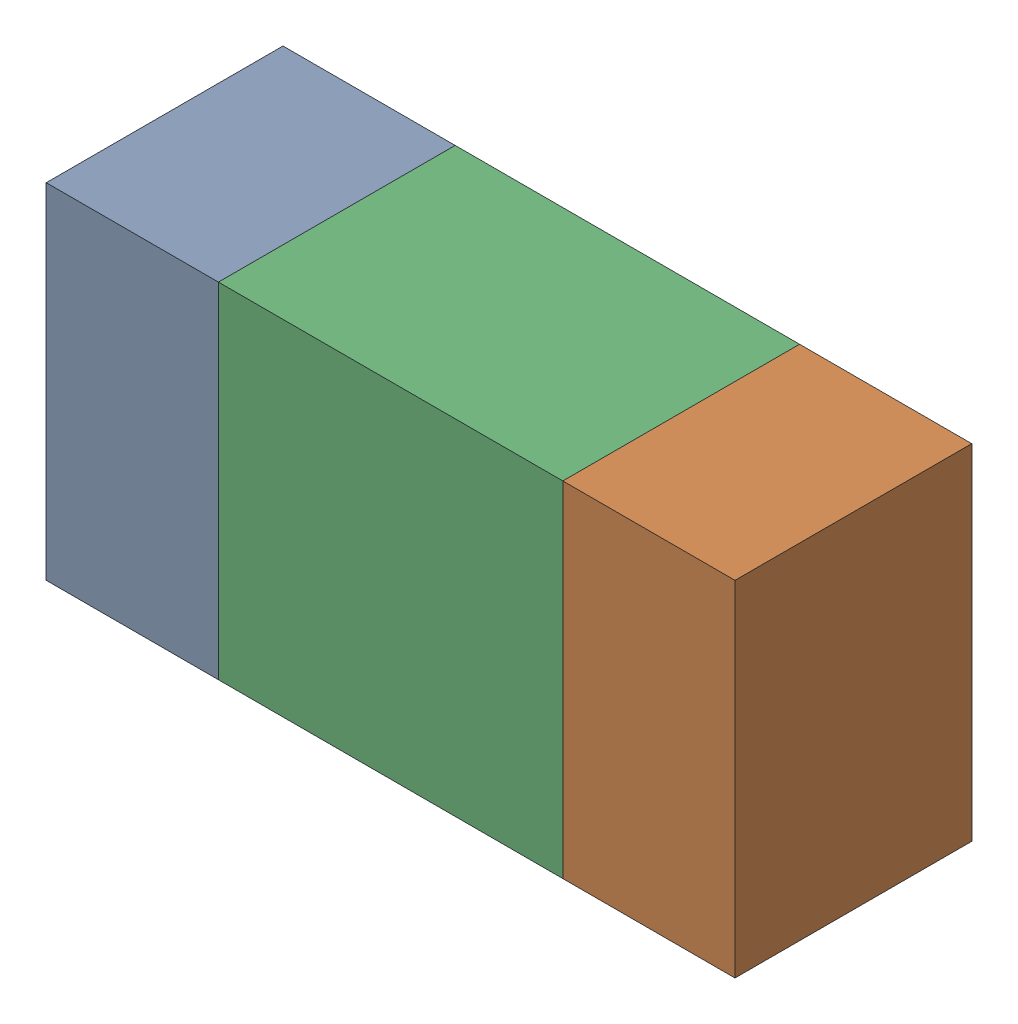
SolidWorks assembly R9, configuration ﾃﾞﾌｫﾙﾄ. Lengths in mm.
Overall size (1.6 0.8 0.55).
6 component instances, 2 part files, 0 mates.
Components (placement in the parent):
- 689261512-1: 689261512 [ﾃﾞﾌｫﾙﾄ] at (6.4001 27.7501 0) size (0.4 0.8 0.55)
  - Extruded_32-1: Extruded_32 [ﾃﾞﾌｫﾙﾄ] at origin size (0.4 0.8 0.55)
- 689261512-2: 689261512 [ﾃﾞﾌｫﾙﾄ] at (7.6001 27.7501 0) size (0.4 0.8 0.55)
  - Extruded_32-1: Extruded_32 [ﾃﾞﾌｫﾙﾄ] at origin size (0.4 0.8 0.55)
- 689261648-1: 689261648 [ﾃﾞﾌｫﾙﾄ] at (7 27.7501 0) size (0.8 0.8 0.55)
  - Extruded_33-1: Extruded_33 [ﾃﾞﾌｫﾙﾄ] at origin size (0.8 0.8 0.55)
